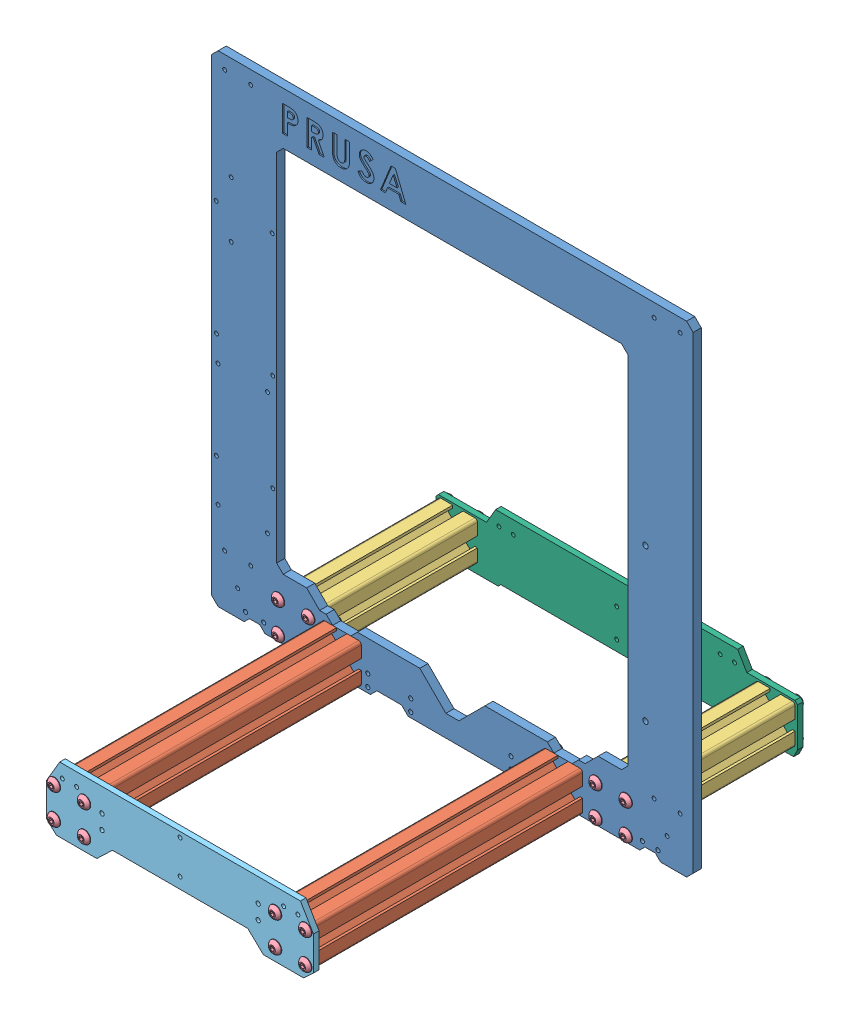
SolidWorks assembly Frame Assembly, configuration Default. Lengths in mm.
Overall size (370 375 345.6).
39 component instances, 6 part files, 82 mates.
Components (placement in the parent):
- i3 MK3 Frame-1: i3 MK3 Frame [Default] at (-79.4742 52.1894 268.1135) size (370 370 6.25)
- Long Extrusion-1: Long Extrusion [Default] at (190.5258 68.6894 274.3635) size (30 30 205)
- Long Extrusion-2: Long Extrusion [Default] at (20.5258 68.6894 274.3635) size (30 30 205)
- Short Extrusion-1: Short Extrusion [Default] at (-16.4742 68.6894 148.1135) size (30 30 120)
- Short Extrusion-2: Short Extrusion [Default] at (227.5258 68.6894 148.1135) size (30 30 120)
- M5-16 Caphead Screw-1: M5-16 Caphead Screw [92095A212] at (239.1258 57.0894 277.1135) size (9.5 9.5 19.24)
- M5-16 Caphead Screw-2: M5-16 Caphead Screw [92095A212] at (8.9287 80.3027 486.3635) size (9.5 9.5 19.24)
- M5-16 Caphead Screw-3: M5-16 Caphead Screw [92095A212] at (202.1295 80.303 486.3635) size (9.5 9.5 19.24)
- M5-16 Caphead Screw-4: M5-16 Caphead Screw [92095A212] at (178.9311 80.3021 486.3635) size (9.5 9.5 19.24)
- M5-16 Caphead Screw-5: M5-16 Caphead Screw [92095A212] at (215.9258 80.2894 277.1135) size (9.5 9.5 19.24)
- M5-16 Caphead Screw-6: M5-16 Caphead Screw [92095A212] at (8.9258 57.0894 486.3635) size (9.5 9.5 19.24)
- M5-16 Caphead Screw-7: M5-16 Caphead Screw [92095A212] at (178.9324 57.0896 486.3635) size (9.5 9.5 19.24)
- M5-16 Caphead Screw-8: M5-16 Caphead Screw [92095A212] at (239.1258 80.2894 277.1135) size (9.5 9.5 19.24)
- M5-16 Caphead Screw-9: M5-16 Caphead Screw [92095A212] at (202.1324 57.0896 486.3635) size (9.5 9.5 19.24)
- M5-16 Caphead Screw-10: M5-16 Caphead Screw [92095A212] at (32.1258 57.0894 486.3635) size (9.5 9.5 19.24)
- M5-16 Caphead Screw-11: M5-16 Caphead Screw [92095A212] at (32.127 80.3019 486.3635) size (9.5 9.5 19.24)
- M5-16 Caphead Screw-12: M5-16 Caphead Screw [92095A212] at (-4.8742 80.2894 277.1135) size (9.5 9.5 19.24)
- M5-16 Caphead Screw-13: M5-16 Caphead Screw [92095A212] at (-4.8742 57.0894 277.1135) size (9.5 9.5 19.24)
- M5-16 Caphead Screw-14: M5-16 Caphead Screw [92095A212] at (-28.0742 80.2894 277.1135) size (9.5 9.5 19.24)
- M5-16 Caphead Screw-15: M5-16 Caphead Screw [92095A212] at (-28.0742 57.0894 277.1135) size (9.5 9.5 19.24)
- M5-16 Caphead Screw-16: M5-16 Caphead Screw [92095A212] at (215.9258 57.0894 277.1135) size (9.5 9.5 19.24)
- M5-16 Caphead Screw-17: M5-16 Caphead Screw [92095A212] at (215.9258 80.2894 141.1135) x (1 0 0) z (0 0 -1) size (9.5 9.5 19.24)
- M5-16 Caphead Screw-18: M5-16 Caphead Screw [92095A212] at (32.1258 80.2894 265.3635) x (1 0 0) z (0 0 -1) size (9.5 9.5 19.24)
- M5-16 Caphead Screw-19: M5-16 Caphead Screw [92095A212] at (202.1258 80.2894 265.3635) x (1 0 0) z (0 0 -1) size (9.5 9.5 19.24)
- M5-16 Caphead Screw-20: M5-16 Caphead Screw [92095A212] at (178.9258 80.2894 265.3635) x (1 0 0) z (0 0 -1) size (9.5 9.5 19.24)
- M5-16 Caphead Screw-21: M5-16 Caphead Screw [92095A212] at (215.926 57.0893 141.1135) x (1 0 0) z (0 0 -1) size (9.5 9.5 19.24)
- M5-16 Caphead Screw-22: M5-16 Caphead Screw [92095A212] at (8.9258 57.0894 265.3635) x (1 0 0) z (0 0 -1) size (9.5 9.5 19.24)
- M5-16 Caphead Screw-23: M5-16 Caphead Screw [92095A212] at (8.9258 80.2894 265.3635) x (1 0 0) z (0 0 -1) size (9.5 9.5 19.24)
- M5-16 Caphead Screw-24: M5-16 Caphead Screw [92095A212] at (239.1258 80.2894 141.1135) x (1 0 0) z (0 0 -1) size (9.5 9.5 19.24)
- M5-16 Caphead Screw-25: M5-16 Caphead Screw [92095A212] at (239.1259 57.0892 141.1135) x (1 0 0) z (0 0 -1) size (9.5 9.5 19.24)
- M5-16 Caphead Screw-26: M5-16 Caphead Screw [92095A212] at (-4.8712 80.276 141.1135) x (1 0 0) z (0 0 -1) size (9.5 9.5 19.24)
- M5-16 Caphead Screw-27: M5-16 Caphead Screw [92095A212] at (-28.0743 80.2892 141.1135) x (1 0 0) z (0 0 -1) size (9.5 9.5 19.24)
- M5-16 Caphead Screw-28: M5-16 Caphead Screw [92095A212] at (-28.072 57.0752 141.1135) x (1 0 0) z (0 0 -1) size (9.5 9.5 19.24)
- M5-16 Caphead Screw-29: M5-16 Caphead Screw [92095A212] at (-4.874 57.0894 141.1135) x (1 0 0) z (0 0 -1) size (9.5 9.5 19.24)
- M5-16 Caphead Screw-30: M5-16 Caphead Screw [92095A212] at (178.9258 57.0894 265.3635) x (1 0 0) z (0 0 -1) size (9.5 9.5 19.24)
- M5-16 Caphead Screw-31: M5-16 Caphead Screw [92095A212] at (202.1258 57.0894 265.3635) x (1 0 0) z (0 0 -1) size (9.5 9.5 19.24)
- M5-16 Caphead Screw-32: M5-16 Caphead Screw [92095A212] at (32.1258 57.0894 265.3635) x (1 0 0) z (0 0 -1) size (9.5 9.5 19.24)
- MK3 Front Plate-1: MK3 Front Plate [Default] at (105.5324 47.1896 479.3635) x (-1 0 0) z (0 0 1) size (205 50 4.25)
- MK3 Rear Plate-1: MK3 Rear Plate [Default] at (105.526 50.1894 143.8635) size (278 50 4.25)
Mates (geometry in assembly coordinates):
- Coincident1: coincident anti-aligned: plane of i3 MK3 Frame-1 through (-79.4742 52.1894 274.3635) normal (0 0 1); plane of Long Extrusion-2 through (20.5258 68.6894 274.3635) normal (0 0 -1)
- Coincident2: coincident anti-aligned: plane of i3 MK3 Frame-1 through (-79.4742 52.1894 274.3635) normal (0 0 1); plane of Long Extrusion-1 through (190.5258 68.6894 274.3635) normal (0 0 -1)
- Coincident3: coincident anti-aligned: plane of i3 MK3 Frame-1 through (-79.4742 52.1894 268.1135) normal (0 0 -1); plane of Short Extrusion-2 through (227.5258 68.6894 268.1135) normal (0 0 1)
- Coincident4: coincident anti-aligned: plane of i3 MK3 Frame-1 through (-79.4742 52.1894 268.1135) normal (0 0 -1); plane of Short Extrusion-1 through (-16.4742 68.6894 268.1135) normal (0 0 1)
- Concentric1: concentric aligned: cylinder of i3 MK3 Frame-1 through (178.9258 80.2894 274.3635) axis (0 0 -1) radius 2.55; cylinder of Long Extrusion-1 through (178.9258 80.2894 479.3635) axis (0 0 -1) radius 2.1
- Concentric2: concentric aligned: cylinder of i3 MK3 Frame-1 through (202.1258 57.0894 274.3635) axis (0 0 -1) radius 2.55; cylinder of Long Extrusion-1 through (202.1258 57.0894 479.3635) axis (0 0 -1) radius 2.1
- Concentric3: concentric aligned: cylinder of i3 MK3 Frame-1 through (239.1258 80.2894 274.3635) axis (0 0 -1) radius 2.55; cylinder of Short Extrusion-2 through (239.1258 80.2894 268.1135) axis (0 0 -1) radius 2.1
- Concentric4: concentric anti-aligned: circle of i3 MK3 Frame-1; cylinder of Short Extrusion-2 through (215.9258 57.0894 268.1135) axis (0 0 -1) radius 2.1
- Concentric7: concentric anti-aligned: circle of i3 MK3 Frame-1; cylinder of Short Extrusion-1 through (-28.0742 57.0894 268.1135) axis (0 0 -1) radius 2.1
- Concentric8: concentric aligned: cylinder of i3 MK3 Frame-1 through (-4.8742 80.2894 274.3635) axis (0 0 -1) radius 2.55; cylinder of Short Extrusion-1 through (-4.8742 80.2894 268.1135) axis (0 0 -1) radius 2.1
- Concentric9: concentric anti-aligned: circle of i3 MK3 Frame-1; cylinder of Long Extrusion-2 through (8.9258 80.2894 479.3635) axis (0 0 -1) radius 2.1
- Concentric10: concentric aligned: cylinder of i3 MK3 Frame-1 through (32.1258 57.0894 274.3635) axis (0 0 -1) radius 2.55; cylinder of Long Extrusion-2 through (32.1258 57.0894 479.3635) axis (0 0 -1) radius 2.1
- Coincident5: coincident anti-aligned: plane of Long Extrusion-1 through (190.5258 68.6894 479.3635) normal (0 0 1); plane of MK3 Front Plate-1 through (105.5324 47.1896 479.3635) normal (0 0 -1)
- Concentric15: concentric aligned: circle of Long Extrusion-2; circle of MK3 Front Plate-1
- Parallel2: parallel aligned: plane of Long Extrusion-1 through (190.5258 83.6894 479.3635) normal (0 1 0); plane of MK3 Front Plate-1 through (198.0324 97.1896 483.6135) normal (0 1 0)
- Concentric16: concentric anti-aligned: cylinder of i3 MK3 Frame-1 through (215.9258 57.0894 274.3635) axis (0 0 -1) radius 2.55; circle of M5-16 Caphead Screw-16
- Coincident7: coincident anti-aligned: plane of i3 MK3 Frame-1 through (-79.4742 52.1894 274.3635) normal (0 0 1); plane of M5-16 Caphead Screw-16 through (215.9258 52.3394 274.3635) normal (0 0 -1)
- Coincident8: coincident anti-aligned: plane of Short Extrusion-2 through (227.5258 68.6894 148.1135) normal (0 0 -1); plane of MK3 Rear Plate-1 through (105.526 50.1894 148.1135) normal (0 0 1)
- Concentric17: concentric anti-aligned: circle of Short Extrusion-2; cylinder of MK3 Rear Plate-1 through (239.1258 80.2894 148.1135) axis (0 0 -1) radius 2.5002
- Parallel3: parallel aligned: plane of Short Extrusion-1 through (-16.4742 83.6894 268.1135) normal (0 1 0); plane of MK3 Rear Plate-1 through (5.526 85.1894 148.1135) normal (0 1 0)
- Coincident10: coincident anti-aligned: plane of i3 MK3 Frame-1 through (-79.4742 52.1894 274.3635) normal (0 0 1); plane of M5-16 Caphead Screw-5 through (215.9258 75.5394 274.3635) normal (0 0 -1)
- Concentric20: concentric anti-aligned: cylinder of i3 MK3 Frame-1 through (215.9258 80.2894 274.3635) axis (0 0 -1) radius 2.55; circle of M5-16 Caphead Screw-5
- Coincident11: coincident anti-aligned: plane of i3 MK3 Frame-1 through (-79.4742 52.1894 274.3635) normal (0 0 1); plane of M5-16 Caphead Screw-1 through (239.1258 52.3394 274.3635) normal (0 0 -1)
- Concentric21: concentric anti-aligned: cylinder of i3 MK3 Frame-1 through (239.1258 57.0894 274.3635) axis (0 0 -1) radius 2.55; circle of M5-16 Caphead Screw-1
- Coincident12: coincident anti-aligned: plane of i3 MK3 Frame-1 through (-79.4742 52.1894 274.3635) normal (0 0 1); plane of M5-16 Caphead Screw-8 through (239.1258 75.5394 274.3635) normal (0 0 -1)
- Concentric22: concentric anti-aligned: cylinder of i3 MK3 Frame-1 through (239.1258 80.2894 274.3635) axis (0 0 -1) radius 2.55; circle of M5-16 Caphead Screw-8
- Coincident13: coincident anti-aligned: plane of M5-16 Caphead Screw-9 through (202.1324 52.3396 483.6135) normal (0 0 -1); plane of MK3 Front Plate-1 through (105.5324 47.1896 483.6135) normal (0 0 1)
- Coincident14: coincident aligned: circle of M5-16 Caphead Screw-7; plane of MK3 Front Plate-1 through (105.5324 47.1896 483.6135) normal (0 0 1)
- Concentric23: concentric anti-aligned: circle of M5-16 Caphead Screw-7; cylinder of MK3 Front Plate-1 through (178.9324 57.0896 483.6135) axis (0 0 -1) radius 2.5
- Concentric24: concentric aligned: circle of M5-16 Caphead Screw-9; circle of MK3 Front Plate-1
- Coincident15: coincident anti-aligned: plane of M5-16 Caphead Screw-4 through (178.9311 75.5521 483.6135) normal (0 0 -1); plane of MK3 Front Plate-1 through (105.5324 47.1896 483.6135) normal (0 0 1)
- Coincident16: coincident anti-aligned: plane of M5-16 Caphead Screw-3 through (202.1295 75.553 483.6135) normal (0 0 -1); plane of MK3 Front Plate-1 through (105.5324 47.1896 483.6135) normal (0 0 1)
- Concentric25: concentric anti-aligned: circle of M5-16 Caphead Screw-4; cylinder of MK3 Front Plate-1 through (178.9311 80.3021 483.6135) axis (0 0 -1) radius 2.4987
- Concentric26: concentric anti-aligned: circle of M5-16 Caphead Screw-3; cylinder of MK3 Front Plate-1 through (202.1295 80.303 483.6135) axis (0 0 -1) radius 2.4999
- Coincident17: coincident anti-aligned: plane of M5-16 Caphead Screw-6 through (8.9258 52.3394 483.6135) normal (0 0 -1); plane of MK3 Front Plate-1 through (105.5324 47.1896 483.6135) normal (0 0 1)
- Coincident18: coincident anti-aligned: plane of M5-16 Caphead Screw-2 through (8.9287 75.5527 483.6135) normal (0 0 -1); plane of MK3 Front Plate-1 through (105.5324 47.1896 483.6135) normal (0 0 1)
- Coincident19: coincident anti-aligned: plane of M5-16 Caphead Screw-10 through (32.1258 52.3394 483.6135) normal (0 0 -1); plane of MK3 Front Plate-1 through (105.5324 47.1896 483.6135) normal (0 0 1)
- Coincident20: coincident anti-aligned: plane of M5-16 Caphead Screw-11 through (32.127 75.5519 483.6135) normal (0 0 -1); plane of MK3 Front Plate-1 through (105.5324 47.1896 483.6135) normal (0 0 1)
- Concentric27: concentric aligned: circle of M5-16 Caphead Screw-6; circle of MK3 Front Plate-1
- Concentric28: concentric anti-aligned: circle of M5-16 Caphead Screw-2; cylinder of MK3 Front Plate-1 through (8.9287 80.3027 483.6135) axis (0 0 -1) radius 2.4999
- Concentric29: concentric anti-aligned: circle of M5-16 Caphead Screw-10; cylinder of MK3 Front Plate-1 through (32.1258 57.0894 483.6135) axis (0 0 -1) radius 2.5
- Concentric30: concentric aligned: circle of M5-16 Caphead Screw-11; circle of MK3 Front Plate-1
- Coincident21: coincident anti-aligned: plane of i3 MK3 Frame-1 through (-79.4742 52.1894 274.3635) normal (0 0 1); plane of M5-16 Caphead Screw-15 through (-28.0742 52.3394 274.3635) normal (0 0 -1)
- Coincident22: coincident anti-aligned: plane of i3 MK3 Frame-1 through (-79.4742 52.1894 274.3635) normal (0 0 1); plane of M5-16 Caphead Screw-14 through (-28.0742 75.5394 274.3635) normal (0 0 -1)
- Coincident23: coincident anti-aligned: plane of i3 MK3 Frame-1 through (-79.4742 52.1894 274.3635) normal (0 0 1); plane of M5-16 Caphead Screw-13 through (-4.8742 52.3394 274.3635) normal (0 0 -1)
- Coincident24: coincident anti-aligned: plane of i3 MK3 Frame-1 through (-79.4742 52.1894 274.3635) normal (0 0 1); plane of M5-16 Caphead Screw-12 through (-4.8742 75.5394 274.3635) normal (0 0 -1)
- Concentric31: concentric anti-aligned: cylinder of i3 MK3 Frame-1 through (-28.0742 57.0894 274.3635) axis (0 0 -1) radius 2.55; circle of M5-16 Caphead Screw-15
- Concentric32: concentric anti-aligned: cylinder of i3 MK3 Frame-1 through (-4.8742 57.0894 274.3635) axis (0 0 -1) radius 2.55; circle of M5-16 Caphead Screw-13
- Concentric33: concentric anti-aligned: cylinder of i3 MK3 Frame-1 through (-28.0742 80.2894 274.3635) axis (0 0 -1) radius 2.55; circle of M5-16 Caphead Screw-14
- Concentric34: concentric aligned: circle of i3 MK3 Frame-1; circle of M5-16 Caphead Screw-12
- Coincident25: coincident aligned: plane of M5-16 Caphead Screw-22 through (8.9258 61.8394 268.1135) normal (0 0 1); plane of M5-16 Caphead Screw-32 through (32.1258 61.8394 268.1135) normal (0 0 1)
- Coincident26: coincident aligned: plane of M5-16 Caphead Screw-18 through (32.1258 85.0394 268.1135) normal (0 0 1); plane of M5-16 Caphead Screw-32 through (32.1258 61.8394 268.1135) normal (0 0 1)
- Coincident27: coincident aligned: plane of M5-16 Caphead Screw-18 through (32.1258 85.0394 268.1135) normal (0 0 1); plane of M5-16 Caphead Screw-19 through (202.1258 85.0394 268.1135) normal (0 0 1)
- Coincident28: coincident aligned: plane of M5-16 Caphead Screw-19 through (202.1258 85.0394 268.1135) normal (0 0 1); plane of M5-16 Caphead Screw-23 through (8.9258 85.0394 268.1135) normal (0 0 1)
- Coincident29: coincident aligned: plane of M5-16 Caphead Screw-23 through (8.9258 85.0394 268.1135) normal (0 0 1); plane of M5-16 Caphead Screw-30 through (178.9258 61.8394 268.1135) normal (0 0 1)
- Coincident30: coincident aligned: plane of M5-16 Caphead Screw-30 through (178.9258 61.8394 268.1135) normal (0 0 1); plane of M5-16 Caphead Screw-31 through (202.1258 61.8394 268.1135) normal (0 0 1)
- Coincident31: coincident aligned: plane of M5-16 Caphead Screw-19 through (202.1258 85.0394 268.1135) normal (0 0 1); plane of M5-16 Caphead Screw-20 through (178.9258 85.0394 268.1135) normal (0 0 1)
- Coincident32: coincident aligned: plane of M5-16 Caphead Screw-25 through (239.1259 61.8392 143.8635) normal (0 0 1); plane of M5-16 Caphead Screw-26 through (-4.8712 85.026 143.8635) normal (0 0 1)
- Coincident33: coincident aligned: plane of M5-16 Caphead Screw-25 through (239.1259 61.8392 143.8635) normal (0 0 1); plane of M5-16 Caphead Screw-28 through (-28.072 61.8252 143.8635) normal (0 0 1)
- Coincident34: coincident aligned: plane of M5-16 Caphead Screw-21 through (215.926 61.8393 143.8635) normal (0 0 1); plane of M5-16 Caphead Screw-25 through (239.1259 61.8392 143.8635) normal (0 0 1)
- Coincident35: coincident aligned: plane of M5-16 Caphead Screw-21 through (215.926 61.8393 143.8635) normal (0 0 1); plane of M5-16 Caphead Screw-24 through (239.1258 85.0394 143.8635) normal (0 0 1)
- Coincident36: coincident aligned: plane of M5-16 Caphead Screw-17 through (215.9258 85.0394 143.8635) normal (0 0 1); plane of M5-16 Caphead Screw-24 through (239.1258 85.0394 143.8635) normal (0 0 1)
- Coincident37: coincident aligned: plane of M5-16 Caphead Screw-21 through (215.926 61.8393 143.8635) normal (0 0 1); plane of M5-16 Caphead Screw-27 through (-28.0743 85.0392 143.8635) normal (0 0 1)
- Coincident38: coincident aligned: plane of M5-16 Caphead Screw-21 through (215.926 61.8393 143.8635) normal (0 0 1); plane of M5-16 Caphead Screw-29 through (-4.874 61.8394 143.8635) normal (0 0 1)
- Coincident39: coincident aligned: plane of i3 MK3 Frame-1 through (-79.4742 52.1894 268.1135) normal (0 0 -1); circle of M5-16 Caphead Screw-19
- Coincident40: coincident anti-aligned: plane of M5-16 Caphead Screw-24 through (239.1258 85.0394 143.8635) normal (0 0 1); plane of MK3 Rear Plate-1 through (105.526 50.1894 143.8635) normal (0 0 -1)
- Concentric35: concentric anti-aligned: circle of Short Extrusion-2; circle of M5-16 Caphead Screw-24
- Concentric36: concentric aligned: cylinder of Short Extrusion-2 through (215.9258 80.2894 268.1135) axis (0 0 -1) radius 2.1; circle of M5-16 Caphead Screw-17
- Concentric37: concentric anti-aligned: circle of M5-16 Caphead Screw-21; circle of MK3 Rear Plate-1
- Concentric38: concentric anti-aligned: circle of M5-16 Caphead Screw-25; circle of MK3 Rear Plate-1
- Concentric39: concentric anti-aligned: circle of i3 MK3 Frame-1; circle of M5-16 Caphead Screw-19
- Concentric40: concentric anti-aligned: circle of M5-16 Caphead Screw-26; circle of MK3 Rear Plate-1
- Concentric41: concentric anti-aligned: circle of M5-16 Caphead Screw-29; circle of MK3 Rear Plate-1
- Concentric42: concentric anti-aligned: circle of M5-16 Caphead Screw-28; circle of MK3 Rear Plate-1
- Concentric43: concentric aligned: circle of M5-16 Caphead Screw-27; cylinder of MK3 Rear Plate-1 through (-28.0743 80.2892 148.1135) axis (0 0 -1) radius 2.5
- Concentric44: concentric anti-aligned: circle of i3 MK3 Frame-1; circle of M5-16 Caphead Screw-31
- Concentric45: concentric anti-aligned: circle of i3 MK3 Frame-1; circle of M5-16 Caphead Screw-30
- Concentric46: concentric aligned: cylinder of i3 MK3 Frame-1 through (178.9258 80.2894 274.3635) axis (0 0 -1) radius 2.55; circle of M5-16 Caphead Screw-20
- Concentric47: concentric anti-aligned: circle of i3 MK3 Frame-1; circle of M5-16 Caphead Screw-23
- Concentric48: concentric anti-aligned: circle of i3 MK3 Frame-1; circle of M5-16 Caphead Screw-22
- Concentric49: concentric aligned: cylinder of i3 MK3 Frame-1 through (32.1258 57.0894 274.3635) axis (0 0 -1) radius 2.55; circle of M5-16 Caphead Screw-32
- Concentric50: concentric anti-aligned: circle of Long Extrusion-2; circle of M5-16 Caphead Screw-18
